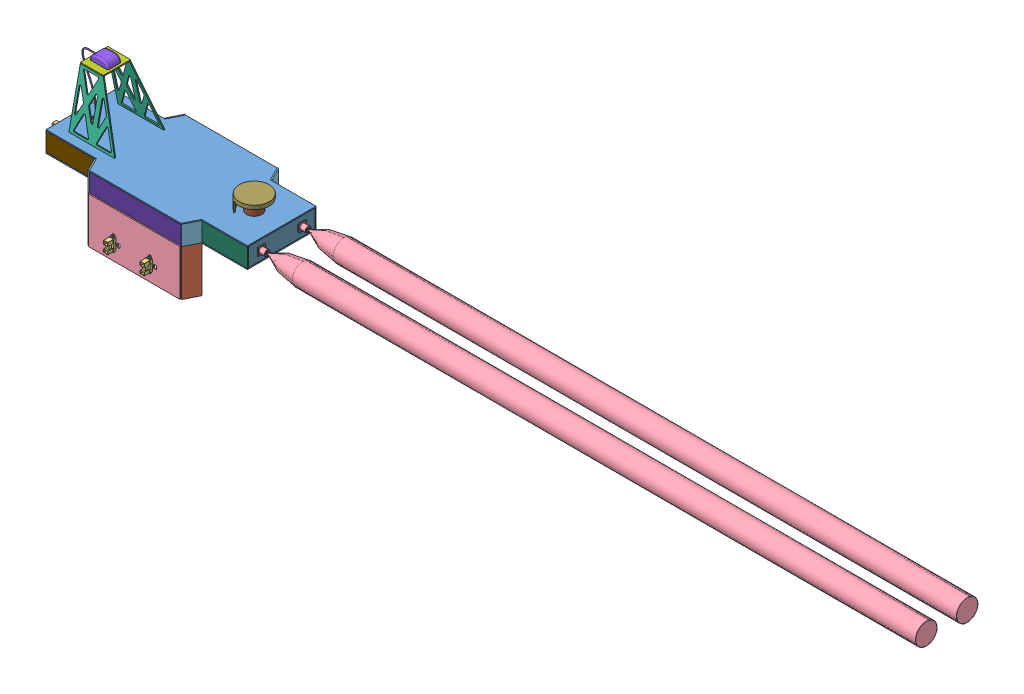
SolidWorks assembly ShellAssem, configuration Default. Lengths in mm.
Overall size (2425.58 352.65 316.25).
56 component instances, 30 part files, 118 mates.
Components (placement in the parent):
- BasePlate-1: BasePlate [Default] at origin size (558.8 3.17 266.7)
- LowerPanelThin-1: LowerPanelThin [Default] at (-130.175 -61.9125 114.3) x (0.447214 0 0.894427) z (-0.894427 0 0.447214) size (42.6 127 3.17)
- LowerPanelThin-2: LowerPanelThin [Default] at (145.7148 -61.9125 115.7199) x (-0.447214 0 0.894427) z (-0.894427 0 -0.447214) size (42.6 127 3.17)
- LowerPanelThin-3: LowerPanelThin [Default] at (-133.0148 -61.9125 -115.7199) x (-0.447214 0 0.894427) z (0.894427 0 0.447214) size (42.6 127 3.17)
- LowerPanelThin-4: LowerPanelThin [Default] at (142.875 -61.9125 -114.3) x (-0.447214 0 -0.894427) z (0.894427 0 -0.447214) size (42.6 127 3.17)
- LowerPanelWideLeft-1: LowerPanelWideLeft [Default] at (6.35 -61.9125 -134.9375) size (254 127 3.17)
- LowerPanelWideRight-1: LowerPanelWideRight [Default] at (6.35 -61.9125 134.9375) size (254 127 3.17)
- BatteryCaseLAssem-1: BatteryCaseLAssem [Default] at (-70.6369 -3.6134 28.4034) x (-1 0 0) z (0 0 -1) size (142.88 26.04 63.5)
  - BatteryCaseShort-1: BatteryCaseShort [Default] at (-92.8619 -9.4041 55.3909) size (114.3 22.86 3.17)
  - BatteryCaseLong-1: BatteryCaseLong [Default] at (-80.1619 -9.4041 115.7159) size (139.7 22.86 3.17)
  - BatteryCaseEnd-1: BatteryCaseEnd [Default] at (-8.7244 -9.4041 95.0784) x (0 0 1) z (0 -1 0) size (44.45 3.17 22.86)
  - Part7^BatteryCaseLAssem-1: Part7^BatteryCaseLAssem [Default] at origin (virtual)
  - Part8^BatteryCaseLAssem-1: Part8^BatteryCaseLAssem [Default] at origin (virtual)
  - Part9-1: Part9 [Default] at (0 -22.4216 0) x (1 0 0) z (0 1 0) size (142.88 63.5 3.17)
- BatteryCaseRAssem-1: BatteryCaseRAssem [Default] at (-70.6369 -22.4216 -28.4034) x (-1 0 0) z (0 0 1) size (142.88 26.04 63.5)
  - BatteryCaseShort-1: BatteryCaseShort [Default] at (-92.8619 -9.4041 55.3909) size (114.3 22.86 3.17)
  - BatteryCaseLong-1: BatteryCaseLong [Default] at (-80.1619 -9.4041 115.7159) size (139.7 22.86 3.17)
  - BatteryCaseEnd-1: BatteryCaseEnd [Default] at (-8.7244 -9.4041 95.0784) x (0 0 1) z (0 -1 0) size (44.45 3.17 22.86)
  - Part7^BatteryCaseRAssem-1: Part7^BatteryCaseRAssem [Default] at origin (virtual)
  - Part8^BatteryCaseRAssem-1: Part8^BatteryCaseRAssem [Default] at origin (virtual)
  - Part9-1: Part9 [Default] at (0 3.6134 0) x (1 0 0) z (0 1 0) size (142.88 63.5 3.17)
- NUC-1: NUC [Default] at (-220.6234 1.5875 -63.9843) size (111 48.26 114.81)
- LIDAR_case-1: LIDAR_case [Default] at (247.65 11.1125 44.45) x (0 0 -1) z (1 0 0) size (88.9 93.99 88.9)
  - LIDAR_base-1: LIDAR_base [Default] at origin size (88.9 11.68 88.9)
  - LIDAR-1: LIDAR [Default] at (19.45 3.0942 -69.45) size (50 70.6 50)
  - LIDAR_top-1: LIDAR_top [Default] at (44.45 2.794 -44.45) x (0 0 -1) z (1 0 0) size (82.55 82.55 82.55)
- UpperRear-1: UpperRear [Default] at (-277.8125 26.9875 0) x (0 0 1) z (-1 0 0) size (184.15 50.8 3.17)
- UpperFront-2: UpperFront [Default] at (277.8125 26.9875 0) x (0 0 1) z (-1 0 0) size (184.15 50.8 3.17)
- UpperFrontWall-1: UpperFrontWall [Default] at (215.9 26.9875 -93.6625) size (127 50.8 3.17)
- UpperFrontWall-2: UpperFrontWall [Default] at (215.9 26.9875 93.6625) size (127 50.8 3.17)
- UpperAngleWallSmall-1: UpperAngleWallSmall [Default] at (141.4718 26.9875 113.5565) x (0.447214 0 -0.894427) z (0.894427 0 0.447214) size (42.67 50.8 3.17)
- UpperAngleWallSmall-3: UpperAngleWallSmall [Default] at (141.4718 26.9875 -113.5565) x (0.447214 0 0.894427) z (-0.894427 0 0.447214) size (42.67 50.8 3.17)
- UpperAngleWallSmall-4: UpperAngleWallSmall [Default] at (-128.7718 26.9875 -113.5565) x (0.447214 0 -0.894427) z (0.894427 0 0.447214) size (42.67 50.8 3.17)
- UpperAngleWallSmall-5: UpperAngleWallSmall [Default] at (-128.7718 26.9875 113.5565) x (-0.447214 0 -0.894427) z (0.894427 0 -0.447214) size (42.67 50.8 3.17)
- UpperAngleWallLarge-1: UpperAngleWallLarge [Default] at (6.35 26.9875 -131.7625) size (254 50.8 3.17)
- UpperAngleWallLarge-2: UpperAngleWallLarge [Default] at (6.35 26.9875 131.7625) size (254 50.8 3.17)
- UpperRearWall-1: UpperRearWall [Default] at (-209.55 26.9875 93.6625) size (139.7 50.8 3.17)
- UpperRearWall-2: UpperRearWall [Default] at (-209.55 26.9875 -93.6625) size (139.7 50.8 3.17)
- CoverPlate-1: CoverPlate [Default] at (0 53.975 0) size (558.8 3.17 266.7)
- LidarLift-1: LidarLift [Default] at (203.2 6.35 0) size (88.9 9.53 88.9)
- OYS-31006-1: OYS-31006 [Default] at (50.605 -82.0125 136.525) x (0 -1 0) z (-1 0 0) size (44.75 21.6 16.37)
- OYS-31006-2: OYS-31006 [Default] at (-50.605 -82.0125 136.525) x (0 -1 0) z (-1 0 0) size (44.75 21.6 16.37)
- OYS-31006-5: OYS-31006 [Default] at (-279.4 26.9875 -50.605) x (0 -1 0) z (0 0 -1) size (44.75 21.6 16.37)
- OYS-31006-7: OYS-31006 [Default] at (-279.4 26.9875 50.605) x (0 -1 0) z (0 0 -1) size (44.75 21.6 16.37)
- OYS-31006-8: OYS-31006 [Default] at (63.305 -82.0125 -136.525) x (0 -1 0) z (1 0 0) size (44.75 21.6 16.37)
- OYS-31006-9: OYS-31006 [Default] at (-63.305 -82.0125 -136.525) x (0 -1 0) z (1 0 0) size (44.75 21.6 16.37)
- SENSOR, SONAR, Maxbotix EZ4-1: SENSOR, SONAR, Maxbotix EZ4 [Default] at (279.4 26.9875 -56.725) x (0 0 1) z (1 0 0) size (60 60 1845.18)
- SENSOR, SONAR, Maxbotix EZ4-2: SENSOR, SONAR, Maxbotix EZ4 [Default] at (279.4 26.9875 56.725) x (0 0 -1) z (1 0 0) size (60 60 1845.18)
- UpperLidCatch-1: UpperLidCatch [Default] at (144.3117 28.575 114.9765) x (0.447214 0 -0.894427) z (0.894427 0 0.447214) size (42.67 53.98 3.17)
- UpperLidCatch-2: UpperLidCatch [Default] at (-131.6117 28.575 114.9765) x (-0.447214 0 -0.894427) z (0.894427 0 -0.447214) size (42.67 53.98 3.17)
- UpperLidCatch-3: UpperLidCatch [Default] at (-131.6117 28.575 -114.9765) x (0.447214 0 -0.894427) z (-0.894427 0 -0.447214) size (42.67 53.98 3.17)
- UpperLidCatch-4: UpperLidCatch [Default] at (144.3117 28.575 -114.9765) x (-0.447214 0 -0.894427) z (0.894427 0 -0.447214) size (42.67 53.98 3.17)
- GPSTowerLeg-1: GPSTowerLeg [Default] at (-209.55 129.7598 -52.4223) x (-1 0 0) z (0 0.208333 -0.978058) size (127 152.4 3.17)
- GPSTowerLeg-2: GPSTowerLeg [Default] at (-209.55 129.7598 52.4223) x (-1 0 0) z (0 -0.208333 -0.978058) size (127 152.4 3.17)
- GPSTowerTop-1: GPSTowerTop [Default] at (-209.55 206.206 0) x (-1 0 0) z (0 -1 0) size (63.5 76.2 3.17)
- GPS Antenna-1: GPS Antenna [Default] at (-207.8695 207.7935 0) size (93.57 166.32 39.53)
Mates (geometry in assembly coordinates):
- Coincident1: coincident anti-aligned: plane of BasePlate-1 through (-139.7 1.5875 95.25) normal (-0.894427 0 0.447214); plane of LowerPanelThin-1 through (-130.175 -61.9125 114.3) normal (0.894427 0 -0.447214)
- Coincident2: coincident aligned: line of BasePlate-1 through (-139.7 1.5875 95.25) axis (0 -1 0); line of LowerPanelThin-1 through (-139.7 1.5875 95.25) axis (0 -1 0)
- Coincident3: coincident aligned: plane of BasePlate-1 through (0 1.5875 0) normal (0 1 0); plane of LowerPanelThin-1 through (-142.5398 1.5875 96.6699) normal (0 1 0)
- Coincident4: coincident anti-aligned: plane of BasePlate-1 through (133.35 1.5875 133.35) normal (0.894427 0 0.447214); plane of LowerPanelThin-2 through (142.875 -61.9125 114.3) normal (-0.894427 0 -0.447214)
- Coincident5: coincident aligned: plane of BasePlate-1 through (0 1.5875 0) normal (0 1 0); plane of LowerPanelThin-2 through (152.4 1.5875 95.25) normal (0 1 0)
- Coincident6: coincident aligned: line of BasePlate-1 through (152.4 1.5875 95.25) axis (0 -1 0); line of LowerPanelThin-2 through (152.4 1.5875 95.25) axis (0 -1 0)
- Coincident7: coincident anti-aligned: plane of BasePlate-1 through (-139.7 1.5875 -95.25) normal (-0.894427 0 -0.447214); plane of LowerPanelThin-3 through (-130.175 -61.9125 -114.3) normal (0.894427 0 0.447214)
- Coincident8: coincident aligned: plane of BasePlate-1 through (0 1.5875 0) normal (0 1 0); plane of LowerPanelThin-3 through (-120.65 1.5875 -133.35) normal (0 1 0)
- Coincident9: coincident aligned: line of BasePlate-1 through (-139.7 1.5875 -95.25) axis (0 -1 0); line of LowerPanelThin-3 through (-139.7 1.5875 -95.25) axis (0 -1 0)
- Coincident10: coincident anti-aligned: plane of BasePlate-1 through (133.35 1.5875 -133.35) normal (0.894427 0 -0.447214); plane of LowerPanelThin-4 through (142.875 -61.9125 -114.3) normal (-0.894427 0 0.447214)
- Coincident11: coincident aligned: plane of BasePlate-1 through (0 1.5875 0) normal (0 1 0); plane of LowerPanelThin-4 through (155.2398 1.5875 -96.6699) normal (0 1 0)
- Coincident12: coincident aligned: line of BasePlate-1 through (152.4 1.5875 -95.25) axis (0 -1 0); line of LowerPanelThin-4 through (152.4 1.5875 -95.25) axis (0 -1 0)
- Coincident13: coincident anti-aligned: plane of BasePlate-1 through (-120.65 1.5875 -133.35) normal (0 0 -1); plane of LowerPanelWideLeft-1 through (6.35 -61.9125 -133.35) normal (0 0 1)
- Coincident14: coincident aligned: plane of BasePlate-1 through (0 1.5875 0) normal (0 1 0); plane of LowerPanelWideLeft-1 through (-120.65 1.5875 -133.35) normal (0 1 0)
- Coincident16: coincident anti-aligned: line of LowerPanelThin-3 through (-120.65 -125.4125 -133.35) axis (0 1 0); line of LowerPanelWideLeft-1 through (-120.65 1.5875 -133.35) axis (0 -1 0)
- Coincident17: coincident anti-aligned: plane of BasePlate-1 through (-120.65 1.5875 133.35) normal (0 0 1); plane of LowerPanelWideRight-1 through (6.35 -61.9125 133.35) normal (0 0 -1)
- Coincident18: coincident aligned: plane of BasePlate-1 through (0 1.5875 0) normal (0 1 0); plane of LowerPanelWideRight-1 through (-120.65 1.5875 136.525) normal (0 1 0)
- Coincident19: coincident anti-aligned: line of LowerPanelThin-1 through (-120.65 -125.4125 133.35) axis (0 1 0); line of LowerPanelWideRight-1 through (-120.65 1.5875 133.35) axis (0 -1 0)
- Coincident21: coincident aligned: line of BasePlate-1 through (-63.5 -1.5875 -88.9) axis (1 0 0); line of BatteryCaseLAssem-1/BatteryCaseLong-1 through (-60.325 -1.5875 -88.9) axis (1 0 0)
- Coincident22: coincident anti-aligned: line of BasePlate-1 through (-63.5 -1.5875 -25.4) axis (0 0 -1); line of BatteryCaseLAssem-1/BatteryCaseEnd-1 through (-63.5 -1.5875 -88.9) axis (0 0 1)
- Coincident23: coincident anti-aligned: line of BasePlate-1 through (-63.5 -1.5875 88.9) axis (1 0 0); line of BatteryCaseRAssem-1/BatteryCaseLong-1 through (79.375 -1.5875 88.9) axis (-1 0 0)
- Coincident24: coincident aligned: line of BasePlate-1 through (-63.5 -1.5875 25.4) axis (0 0 1); line of BatteryCaseRAssem-1/BatteryCaseEnd-1 through (-63.5 -1.5875 44.45) axis (0 0 1)
- Coincident25: coincident anti-aligned: plane of BasePlate-1 through (0 1.5875 0) normal (0 1 0); plane of NUC-1 through (-220.6234 1.5875 50.8237) normal (0 -1 0)
- Parallel2: parallel anti-aligned: plane of BasePlate-1 through (-279.4 1.5875 -95.25) normal (-1 0 0); plane of LIDAR_case-1/LIDAR-1 through (228.2 14.2067 25) normal (1 0 0)
- Coincident31: coincident anti-aligned: line of BasePlate-1 through (-276.225 1.5875 92.075) axis (0 0 -1); line of UpperRear-1 through (-276.225 1.5875 -92.075) axis (0 0 1)
- Coincident32: coincident anti-aligned: line of BasePlate-1 through (-279.4 1.5875 95.25) axis (0 0 -1); line of UpperRear-1 through (-279.4 1.5875 -92.075) axis (0 0 1)
- Coincident33: coincident: point of assembly; point of BasePlate-1; point of UpperRear-1
- Coincident34: coincident aligned: line of BasePlate-1 through (276.225 1.5875 -92.075) axis (0 0 1); line of UpperFront-2 through (276.225 1.5875 -92.075) axis (0 0 1)
- Coincident35: coincident aligned: line of BasePlate-1 through (279.4 1.5875 -95.25) axis (0 0 1); line of UpperFront-2 through (279.4 1.5875 -92.075) axis (0 0 1)
- Coincident36: coincident: point of assembly; point of BasePlate-1; point of UpperFront-2
- Coincident37: coincident anti-aligned: plane of UpperFront-2 through (276.225 1.5875 -92.075) normal (0 0 -1); plane of UpperFrontWall-1 through (215.9 26.9875 -92.075) normal (0 0 1)
- Coincident38: coincident anti-aligned: plane of BasePlate-1 through (0 1.5875 0) normal (0 1 0); plane of UpperFrontWall-1 through (152.4 1.5875 -92.075) normal (0 -1 0)
- Coincident39: coincident aligned: plane of BasePlate-1 through (279.4 1.5875 -95.25) normal (1 0 0); plane of UpperFrontWall-1 through (279.4 1.5875 -92.075) normal (1 0 0)
- Coincident40: coincident anti-aligned: plane of BasePlate-1 through (0 1.5875 0) normal (0 1 0); plane of UpperFrontWall-2 through (152.4 1.5875 95.25) normal (0 -1 0)
- Coincident41: coincident aligned: plane of BasePlate-1 through (279.4 1.5875 -95.25) normal (1 0 0); plane of UpperFrontWall-2 through (279.4 1.5875 95.25) normal (1 0 0)
- Coincident42: coincident aligned: plane of BasePlate-1 through (152.4 1.5875 95.25) normal (0 0 1); plane of UpperFrontWall-2 through (215.9 26.9875 95.25) normal (0 0 1)
- Coincident43: coincident anti-aligned: plane of BasePlate-1 through (0 1.5875 0) normal (0 1 0); plane of UpperAngleWallSmall-1 through (133.35 1.5875 133.35) normal (0 -1 0)
- Coincident44: coincident anti-aligned: line of BasePlate-1 through (152.4 1.5875 95.25) axis (-0.447214 0 0.894427); line of UpperAngleWallSmall-1 through (133.35 1.5875 133.35) axis (0.447214 0 -0.894427)
- Coincident45: coincident: point of assembly; point of BasePlate-1; point of UpperAngleWallSmall-1
- Coincident47: coincident anti-aligned: plane of BasePlate-1 through (0 1.5875 0) normal (0 1 0); plane of UpperAngleWallSmall-5 through (-117.8102 1.5875 131.9301) normal (0 -1 0)
- Coincident48: coincident aligned: line of BasePlate-1 through (-120.65 1.5875 133.35) axis (-0.447214 0 -0.894427); line of UpperAngleWallSmall-5 through (-120.65 1.5875 133.35) axis (-0.447214 0 -0.894427)
- Coincident49: coincident: point of assembly; point of BasePlate-1; point of UpperAngleWallSmall-5
- Coincident50: coincident anti-aligned: plane of BasePlate-1 through (0 1.5875 0) normal (0 1 0); plane of UpperAngleWallSmall-4 through (-136.8937 1.5875 -93.7631) normal (0 -1 0)
- Coincident51: coincident aligned: line of BasePlate-1 through (-139.7 1.5875 -95.25) axis (0.447214 0 -0.894427); line of UpperAngleWallSmall-4 through (-139.7335 1.5875 -95.183) axis (0.447214 0 -0.894427)
- Coincident52: coincident: point of BasePlate-1; point of UpperAngleWallSmall-4
- Coincident53: coincident anti-aligned: plane of BasePlate-1 through (0 1.5875 0) normal (0 1 0); plane of UpperAngleWallSmall-3 through (130.5102 1.5875 -131.9301) normal (0 -1 0)
- Coincident54: coincident aligned: line of BasePlate-1 through (133.35 1.5875 -133.35) axis (0.447214 0 0.894427); line of UpperAngleWallSmall-3 through (133.35 1.5875 -133.35) axis (0.447214 0 0.894427)
- Coincident56: coincident: point of assembly; point of BasePlate-1; point of UpperAngleWallSmall-3
- Coincident57: coincident anti-aligned: plane of BasePlate-1 through (0 1.5875 0) normal (0 1 0); plane of UpperAngleWallLarge-1 through (-120.65 1.5875 -130.175) normal (0 -1 0)
- Coincident58: coincident aligned: line of BasePlate-1 through (-120.65 1.5875 -133.35) axis (1 0 0); line of UpperAngleWallLarge-1 through (-120.65 1.5875 -133.35) axis (1 0 0)
- Coincident59: coincident anti-aligned: line of UpperAngleWallSmall-4 through (-120.65 1.5875 -133.35) axis (0 1 0); line of UpperAngleWallLarge-1 through (-120.65 52.3875 -133.35) axis (0 -1 0)
- Coincident60: coincident anti-aligned: plane of BasePlate-1 through (0 1.5875 0) normal (0 1 0); plane of UpperAngleWallLarge-2 through (-120.65 1.5875 133.35) normal (0 -1 0)
- Coincident61: coincident anti-aligned: line of BasePlate-1 through (133.35 1.5875 133.35) axis (-1 0 0); line of UpperAngleWallLarge-2 through (-120.65 1.5875 133.35) axis (1 0 0)
- Coincident62: coincident anti-aligned: line of UpperAngleWallSmall-1 through (133.35 52.3875 133.35) axis (0 -1 0); line of UpperAngleWallLarge-2 through (133.35 1.5875 133.35) axis (0 1 0)
- Coincident63: coincident anti-aligned: plane of BasePlate-1 through (0 1.5875 0) normal (0 1 0); plane of UpperRearWall-1 through (-279.4 1.5875 95.25) normal (0 -1 0)
- Coincident64: coincident anti-aligned: line of BasePlate-1 through (-139.7 1.5875 95.25) axis (-1 0 0); line of UpperRearWall-1 through (-279.4 1.5875 95.25) axis (1 0 0)
- Coincident65: coincident aligned: plane of UpperRear-1 through (-279.4 26.9875 0) normal (-1 0 0); plane of UpperRearWall-1 through (-279.4 1.5875 95.25) normal (-1 0 0)
- Coincident66: coincident aligned: plane of UpperRear-1 through (-279.4 26.9875 0) normal (-1 0 0); plane of UpperRearWall-2 through (-279.4 1.5875 -92.075) normal (-1 0 0)
- Coincident67: coincident anti-aligned: plane of BasePlate-1 through (0 1.5875 0) normal (0 1 0); plane of UpperRearWall-2 through (-279.4 1.5875 -92.075) normal (0 -1 0)
- Coincident68: coincident aligned: plane of BasePlate-1 through (-279.4 1.5875 -95.25) normal (0 0 -1); plane of UpperRearWall-2 through (-209.55 26.9875 -95.25) normal (0 0 -1)
- Coincident69: coincident anti-aligned: plane of UpperFrontWall-1 through (152.4 52.3875 -92.075) normal (0 1 0); plane of CoverPlate-1 through (0 52.3875 0) normal (0 -1 0)
- Coincident70: coincident aligned: plane of UpperAngleWallSmall-3 through (142.8917 26.9875 -114.2665) normal (0.894427 0 -0.447214); plane of CoverPlate-1 through (133.35 55.5625 -133.35) normal (0.894427 0 -0.447214)
- Coincident71: coincident aligned: plane of UpperAngleWallSmall-1 through (142.8917 26.9875 114.2665) normal (0.894427 0 0.447214); plane of CoverPlate-1 through (133.35 55.5625 133.35) normal (0.894427 0 0.447214)
- Coincident73: coincident aligned: circle of BasePlate-1; circle of LidarLift-1
- Coincident74: coincident aligned: circle of LIDAR_case-1/LIDAR_base-1; circle of LidarLift-1
- Coincident75: coincident anti-aligned: plane of LowerPanelWideRight-1 through (6.35 -61.9125 136.525) normal (0 0 1); plane of OYS-31006-1 through (50.605 -82.0125 136.525) normal (0 0 -1)
- Parallel5: parallel anti-aligned: plane of LowerPanelWideRight-1 through (133.35 -125.4125 136.525) normal (1 0 0); plane of OYS-31006-1 through (44.06 -67.1875 143.725) normal (-1 0 0)
- Coincident80: coincident anti-aligned: plane of LowerPanelWideRight-1 through (6.35 -61.9125 136.525) normal (0 0 1); plane of OYS-31006-2 through (-50.605 -82.0125 136.525) normal (0 0 -1)
- Parallel6: parallel aligned: plane of LowerPanelWideRight-1 through (-120.65 -125.4125 136.525) normal (-1 0 0); plane of OYS-31006-2 through (-57.15 -67.1875 143.725) normal (-1 0 0)
- Coincident86: coincident aligned: plane of OYS-31006-1 through (45.105 -67.1875 143.725) normal (0 0.999962 0.008727); plane of OYS-31006-2 through (-56.105 -67.1875 143.725) normal (0 0.999962 0.008727)
- Symmetric1: symmetric aligned: plane of OYS-31006-1 through (44.06 -67.1875 143.725) normal (-1 0 0); plane of OYS-31006-2 through (-44.06 -67.1875 143.725) normal (1 0 0)
- Distance4: distance = 28.575 mm aligned: plane of OYS-31006-1 through (44.06 -96.8375 143.725) normal (0 -1 0); plane of LowerPanelWideRight-1 through (-120.65 -125.4125 136.525) normal (0 -1 0)
- Distance5: distance = 63.5 mm: plane of OYS-31006-2 through (-57.15 -67.1875 143.725) normal (-1 0 0); line of LowerPanelWideRight-1 through (-120.65 1.5875 136.525) axis (0 -1 0)
- Coincident92: coincident anti-aligned: plane of UpperRear-1 through (-279.4 26.9875 0) normal (-1 0 0); plane of OYS-31006-5 through (-279.4 26.9875 -50.605) normal (1 0 0)
- Coincident94: coincident anti-aligned: plane of UpperRear-1 through (-279.4 26.9875 0) normal (-1 0 0); plane of OYS-31006-7 through (-279.4 26.9875 50.605) normal (1 0 0)
- Perpendicular1: perpendicular: plane of UpperRear-1 through (-279.4 26.9875 0) normal (-1 0 0); plane of OYS-31006-5 through (-286.6 41.8125 -57.15) normal (0 0 -1)
- Parallel14: parallel aligned: plane of OYS-31006-5 through (-286.6 41.8125 -57.15) normal (0 0 -1); plane of OYS-31006-7 through (-286.6 41.8125 44.06) normal (0 0 -1)
- Coincident97: coincident aligned: plane of OYS-31006-5 through (-286.6 12.1625 -57.15) normal (0 -1 0); plane of OYS-31006-7 through (-286.6 12.1625 44.06) normal (0 -1 0)
- Symmetric2: symmetric aligned: plane of OYS-31006-5 through (-286.6 41.8125 -44.06) normal (0 0 1); plane of OYS-31006-7 through (-286.6 41.8125 44.06) normal (0 0 -1)
- Distance6: distance = 38.1 mm aligned: plane of OYS-31006-5 through (-286.6 41.8125 -57.15) normal (0 0 -1); plane of UpperRearWall-2 through (-209.55 26.9875 -95.25) normal (0 0 -1)
- Width1: width aligned: plane of UpperRear-1 through (-279.4 1.5875 -92.075) normal (0 -1 0); plane of OYS-31006-5 through (-279.4 52.3875 -92.075) normal (0 1 0); plane of UpperRear-1 through (-286.6 41.8125 -56.105) normal (-0.008727 0.999962 0); plane of OYS-31006-5 through (-286.6 12.1625 -56.105) normal (-0.008727 -0.999962 0)
- Coincident99: coincident anti-aligned: plane of LowerPanelWideLeft-1 through (6.35 -61.9125 -136.525) normal (0 0 -1); plane of OYS-31006-8 through (63.305 -82.0125 -136.525) normal (0 0 1)
- Coincident101: coincident anti-aligned: plane of LowerPanelWideLeft-1 through (6.35 -61.9125 -136.525) normal (0 0 -1); plane of OYS-31006-9 through (-63.305 -82.0125 -136.525) normal (0 0 1)
- Symmetric3: symmetric aligned: plane of OYS-31006-8 through (56.76 -67.1875 -143.725) normal (-1 0 0); plane of OYS-31006-9 through (-56.76 -67.1875 -143.725) normal (1 0 0)
- Coincident102: coincident aligned: plane of OYS-31006-8 through (69.85 -96.8375 -143.725) normal (0 -1 0); plane of OYS-31006-9 through (-56.76 -96.8375 -143.725) normal (0 -1 0)
- Distance7: distance = 63.5 mm aligned: plane of OYS-31006-8 through (69.85 -67.1875 -143.725) normal (1 0 0); plane of LowerPanelWideLeft-1 through (133.35 -125.4125 -133.35) normal (1 0 0)
- Distance8: distance = 28.575 mm aligned: plane of OYS-31006-8 through (69.85 -96.8375 -143.725) normal (0 -1 0); plane of LowerPanelWideLeft-1 through (-120.65 -125.4125 -133.35) normal (0 -1 0)
- Coincident105: coincident anti-aligned: plane of UpperFront-2 through (279.4 26.9875 0) normal (1 0 0); plane of SENSOR, SONAR, Maxbotix EZ4-1 through (279.4 15.9375 -46.775) normal (-1 0 0)
- Coincident106: coincident anti-aligned: plane of UpperFront-2 through (279.4 26.9875 0) normal (1 0 0); plane of SENSOR, SONAR, Maxbotix EZ4-2 through (279.4 38.0375 46.775) normal (-1 0 0)
- Coincident107: coincident aligned: plane of BasePlate-1 through (0 0 0) normal (0 0 1)
- Coincident108: coincident aligned: plane of BasePlate-1 through (0 0 0) normal (0 1 0)
- Coincident109: coincident aligned: plane of BasePlate-1 through (0 0 0) normal (1 0 0)
- Symmetric4: symmetric aligned: plane of SENSOR, SONAR, Maxbotix EZ4-1 through (280.9875 38.0375 -46.775) normal (0 0 1); plane of SENSOR, SONAR, Maxbotix EZ4-2 through (280.9875 15.9375 46.775) normal (0 0 -1)
- Width2: width anti-aligned: plane of UpperFront-2 through (276.225 52.3875 -92.075) normal (0 1 0); plane of SENSOR, SONAR, Maxbotix EZ4-1 through (276.225 1.5875 -92.075) normal (0 -1 0); plane of UpperFront-2 through (280.9875 38.0375 -66.675) normal (0 1 0); plane of SENSOR, SONAR, Maxbotix EZ4-1 through (280.9875 15.9375 -66.675) normal (0 -1 0)
- Coincident112: coincident aligned: plane of SENSOR, SONAR, Maxbotix EZ4-1 through (280.9875 38.0375 -66.675) normal (0 1 0); plane of SENSOR, SONAR, Maxbotix EZ4-2 through (280.9875 38.0375 66.675) normal (0 1 0)
- Distance10: distance = 25.4 mm aligned: plane of SENSOR, SONAR, Maxbotix EZ4-2 through (280.9875 15.9375 66.675) normal (0 0 1); plane of UpperFront-2 through (276.225 1.5875 92.075) normal (0 0 1)
- Coincident114: coincident anti-aligned: plane of CoverPlate-1 through (133.35 55.5625 133.35) normal (0.894427 0 0.447214); plane of UpperLidCatch-1 through (142.8917 28.575 114.2665) normal (-0.894427 0 -0.447214)
- Coincident115: coincident aligned: plane of CoverPlate-1 through (0 55.5625 0) normal (0 1 0); plane of UpperLidCatch-1 through (136.1898 55.5625 134.7699) normal (0 1 0)
- Coincident116: coincident aligned: line of CoverPlate-1 through (133.35 55.5625 133.35) axis (0 -1 0); line of UpperLidCatch-1 through (133.35 55.5625 133.35) axis (0 -1 0)
- Coincident118: coincident anti-aligned: plane of CoverPlate-1 through (-139.7 55.5625 95.25) normal (-0.894427 0 0.447214); plane of UpperLidCatch-2 through (-130.1917 28.575 114.2665) normal (0.894427 0 -0.447214)
- Coincident120: coincident aligned: plane of CoverPlate-1 through (0 55.5625 0) normal (0 1 0); plane of UpperLidCatch-2 through (-120.65 55.5625 133.35) normal (0 1 0)
- Coincident121: coincident aligned: line of CoverPlate-1 through (-120.65 55.5625 133.35) axis (0 -1 0); line of UpperLidCatch-2 through (-120.65 55.5625 133.35) axis (0 -1 0)
- Coincident122: coincident anti-aligned: plane of CoverPlate-1 through (-139.7 55.5625 -95.25) normal (-0.894427 0 -0.447214); plane of UpperLidCatch-3 through (-130.1917 28.575 -114.2665) normal (0.894427 0 0.447214)
- Coincident123: coincident aligned: plane of CoverPlate-1 through (0 55.5625 0) normal (0 1 0); plane of UpperLidCatch-3 through (-142.5733 55.5625 -96.6029) normal (0 1 0)
- Coincident124: coincident aligned: line of CoverPlate-1 through (-120.65 55.5625 -133.35) axis (0 -1 0); line of UpperLidCatch-3 through (-120.65 55.5625 -133.35) axis (0 -1 0)
- Coincident126: coincident anti-aligned: plane of CoverPlate-1 through (133.35 55.5625 -133.35) normal (0.894427 0 -0.447214); plane of UpperLidCatch-4 through (142.8917 28.575 -114.2665) normal (-0.894427 0 0.447214)
- Coincident127: coincident aligned: plane of CoverPlate-1 through (0 55.5625 0) normal (0 1 0); plane of UpperLidCatch-4 through (155.2733 55.5625 -96.6029) normal (0 1 0)
- Coincident129: coincident anti-aligned: line of CoverPlate-1 through (133.35 55.5625 -133.35) axis (0 -1 0); line of UpperLidCatch-4 through (133.35 1.5875 -133.35) axis (0 1 0)
- Coincident130: coincident anti-aligned: line of CoverPlate-1 through (-241.3 55.5625 -69.85) axis (1 0 0); line of GPSTowerLeg-1 through (-114.3 55.5625 -69.85) axis (-1 0 0)
- Coincident131: coincident: line of CoverPlate-1 through (-177.8 55.5625 -69.85) axis (0 0 1); plane of GPSTowerLeg-1 through (-177.8 55.5625 -69.85) normal (1 0 0)
- Coincident132: coincident anti-aligned: line of CoverPlate-1 through (-241.3 55.5625 69.85) axis (1 0 0); line of GPSTowerLeg-2 through (-114.3 55.5625 69.85) axis (-1 0 0)
- Coincident133: coincident: line of CoverPlate-1 through (-241.3 55.5625 69.85) axis (0 0 -1); plane of GPSTowerLeg-2 through (-241.3 54.901 66.7447) normal (-1 0 0)
- Coincident134: coincident aligned: line of GPSTowerLeg-1 through (-241.3 204.6185 -38.1) axis (1 0 0); line of GPSTowerTop-1 through (-241.3 204.6185 -38.1) axis (1 0 0)
- Coincident135: coincident aligned: plane of GPSTowerLeg-1 through (-241.3 55.5625 -69.85) normal (-1 0 0); plane of GPSTowerTop-1 through (-241.3 204.6185 38.1) normal (-1 0 0)
- Coincident136: coincident anti-aligned: line of GPSTowerLeg-2 through (-241.3 204.6185 38.1) axis (1 0 0); line of GPSTowerTop-1 through (-177.8 204.6185 38.1) axis (-1 0 0)
- Parallel15: parallel aligned: plane of CoverPlate-1 through (0 55.5625 0) normal (0 1 0); plane of GPSTowerTop-1 through (-209.55 207.7935 0) normal (0 1 0)
- Coincident138: coincident anti-aligned: plane of GPSTowerTop-1 through (-209.55 207.7935 0) normal (0 1 0); plane of GPS Antenna-1 through (-207.8695 207.7935 0) normal (0 -1 0)
- Width3: width anti-aligned: plane of GPSTowerTop-1 through (-177.8 204.6185 38.1) normal (0 0 1); plane of GPS Antenna-1 through (-177.8 204.6185 -38.1) normal (0 0 -1); plane of GPSTowerTop-1 through (-231.9995 227.0975 -19.05) normal (0 0 -1); plane of GPS Antenna-1 through (-231.9995 227.0975 19.05) normal (0 0 1)
